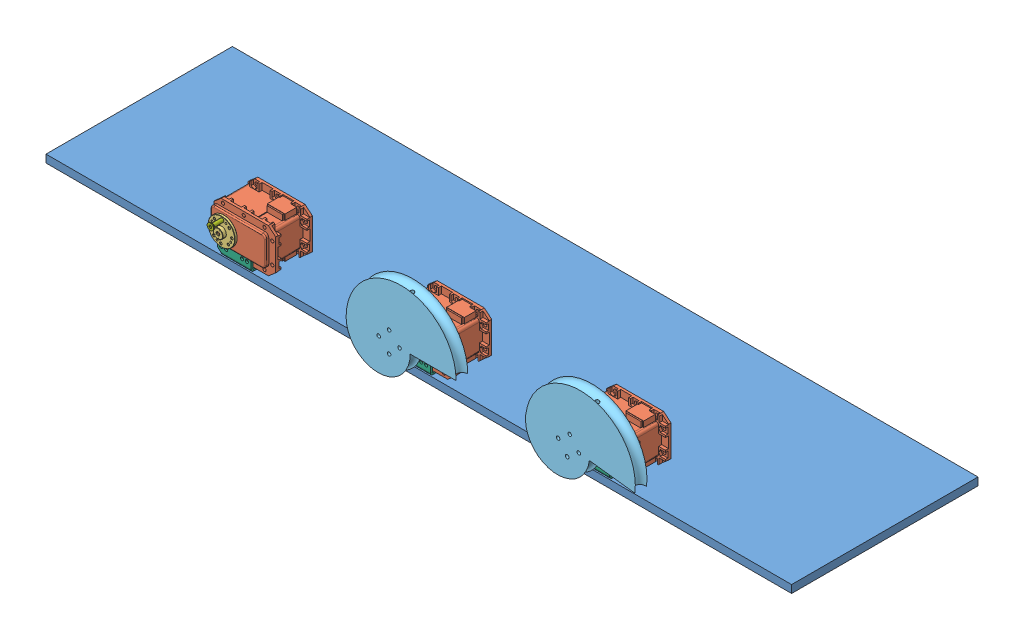
SolidWorks assembly Testing Rig, configuration Default. Lengths in mm.
Overall size (609.6 81.47 166.18).
21 component instances, 7 part files, 30 mates.
Components (placement in the parent):
- Servo Test Plate-1: Servo Test Plate [Default] at (-31.9678 4.9345 11.3595) size (609.6 6.35 152.4)
- MX-28T-1: MX-28T [Default] at (-172.2343 83.1368 48.302) x (0 1 0) z (0 0 1) size (35.6 53.27 43.4) (flexible)
  - MX-28T-1: MX-28T [Default] at (-50.8523 16.8335 22.7575) size (35.6 50.6 41.85)
  - HN07-N1-1: HN07-N1 [Default] at (-50.8523 16.8335 41.5075) x (-0.4309 -0.9024 0) z (-0.9024 0.4309 0) size (22 5.86 22)
  - HN07-i1-1: HN07-i1 [Default] at (-50.8523 16.8335 2.9575) x (0.322877 -0.946441 0) z (0.946441 0.322877 0) size (22 3.05 22)
- MX-28T-2: MX-28T [Default] at (-25.6343 83.1368 48.302) x (0 1 0) z (0 0 1) size (35.6 52.97 43.4) (flexible)
  - MX-28T-1: MX-28T [Default] at (-50.8523 16.8335 22.7575) size (35.6 50.6 41.85)
  - HN07-N1-1: HN07-N1 [Default] at (-50.8523 16.8335 41.5075) x (0.382157 0.924098 0) z (0.924098 -0.382157 0) size (22 5.86 22)
  - HN07-i1-1: HN07-i1 [Default] at (-50.8523 16.8335 2.9575) x (0.322877 -0.946441 0) z (0.946441 0.322877 0) size (22 3.05 22)
- MX-28T-3: MX-28T [Default] at (120.9657 83.1368 48.302) x (0 1 0) z (0 0 1) size (35.6 52.56 43.4) (flexible)
  - MX-28T-1: MX-28T [Default] at (-50.8523 16.8335 22.7575) size (35.6 50.6 41.85)
  - HN07-N1-1: HN07-N1 [Default] at (-50.8523 16.8335 41.5075) x (0.120217 0.992748 0) z (0.992748 -0.120217 0) size (22 5.86 22)
  - HN07-i1-1: HN07-i1 [Default] at (-50.8523 16.8335 2.9575) x (0.322877 -0.946441 0) z (0.946441 0.322877 0) size (22 3.05 22)
- Nautilus Horn-1: Nautilus Horn [Default] at (-189.0678 32.2846 96.572) x (-0.998607 0.052766 0) z (0 0 1) size (89.93 71.18 9.53) (hidden)
- Nautilus Horn-2: Nautilus Horn [Default] at (-42.4678 32.2844 96.572) x (1 0.00057 0) z (0 0 1) size (89.93 71.18 9.53)
- Nautilus Horn-3: Nautilus Horn [Default] at (104.1322 32.2844 96.572) x (0.992748 -0.120217 0) z (0 0 1) size (89.93 71.18 9.53)
- FR07-S101 Bracket-1: FR07-S101 Bracket [Default] at (-181.0678 11.2845 71.0595) size (27.5 8.6 33.01)
- FR07-S101 Bracket-2: FR07-S101 Bracket [Default] at (-34.4678 11.2845 71.0595) size (27.5 8.6 33.01)
- FR07-S101 Bracket-3: FR07-S101 Bracket [Default] at (112.1322 11.2845 71.0595) size (27.5 8.6 33.01)
- socket countersunk head screw_am-1: socket countersunk head screw_am [B18.3.5M - 3 x 0.5 x 12 Socket FCHS  -- 12N] at (-188.846 4.3245 63.2813) x (0 1 0) z (0 0 1) size (12 5.35 5.35)
- socket countersunk head screw_am-2: socket countersunk head screw_am [B18.3.5M - 3 x 0.5 x 12 Socket FCHS  -- 12N] at (-188.6193 40.7729 101.3345) x (0 0 -1) z (1 0 0) size (12 5.35 5.35)
Mates (geometry in assembly coordinates):
- Concentric2: concentric aligned: cylinder of MX-28T-1/HN07-N1-1 through (-189.0678 32.2845 94.952) axis (0 0 -1) radius 11; cylinder of Nautilus Horn-1 through (-189.0678 32.2846 101.3345) axis (0 0 -1) radius 4.0005
- Concentric3: concentric anti-aligned: cylinder of MX-28T-1/HN07-N1-1 through (-189.5163 23.7963 88.0452) axis (0 0 1) radius 0.8; cylinder of Nautilus Horn-1 through (-189.5163 23.7963 91.8095) axis (0 0 -1) radius 1.45
- Parallel1: parallel anti-aligned: plane of Servo Test Plate-1 through (-31.9678 11.2845 11.3595) normal (0 1 0); plane of MX-28T-1/MX-28T-1 through (-195.0678 14.4845 58.0595) normal (0 -1 0)
- Coincident2: coincident anti-aligned: plane of MX-28T-1/MX-28T-1 through (-189.0678 32.2845 56.0595) normal (0 0 -1); plane of FR07-S101 Bracket-1 through (-169.0678 13.2845 56.0595) normal (0 0 1)
- Concentric4: concentric aligned: cylinder of MX-28T-1/MX-28T-1 through (-176.5678 17.2845 71.0595) axis (0 0 -1) radius 1.35; cylinder of FR07-S101 Bracket-1 through (-176.5678 17.2845 87.5595) axis (0 0 -1) radius 1.3
- Coincident3: coincident anti-aligned: plane of Servo Test Plate-1 through (-31.9678 11.2845 11.3595) normal (0 1 0); plane of FR07-S101 Bracket-1 through (-169.0678 11.2845 85.5595) normal (0 -1 0)
- Coincident4: coincident aligned: plane of Servo Test Plate-1 through (-336.7678 11.2845 87.5595) normal (0 0 1); plane of FR07-S101 Bracket-1 through (-169.0678 19.8845 87.5595) normal (0 0 1)
- Coincident5: coincident anti-aligned: plane of MX-28T-1/HN07-N1-1 through (-189.0678 32.2845 91.8095) normal (0 0 1); plane of Nautilus Horn-1 through (-189.0678 32.2846 91.8095) normal (0 0 -1)
- Concentric5: concentric aligned: cylinder of MX-28T-2/HN07-N1-1 through (-42.4678 32.2845 94.952) axis (0 0 -1) radius 4; cylinder of Nautilus Horn-2 through (-42.4678 32.2844 101.3345) axis (0 0 -1) radius 4.0005
- Coincident7: coincident anti-aligned: plane of MX-28T-2/HN07-N1-1 through (-42.4678 32.2845 91.8095) normal (0 0 1); plane of Nautilus Horn-2 through (-42.4678 32.2844 91.8095) normal (0 0 -1)
- Concentric6: concentric anti-aligned: cylinder of MX-28T-2/HN07-N1-1 through (-42.4726 40.7845 88.0452) axis (0 0 1) radius 0.8; cylinder of Nautilus Horn-2 through (-42.4726 40.7845 91.8095) axis (0 0 -1) radius 1.45
- Coincident8: coincident anti-aligned: plane of MX-28T-2/MX-28T-1 through (-42.4678 32.2845 56.0595) normal (0 0 -1); plane of FR07-S101 Bracket-2 through (-22.4678 13.2845 56.0595) normal (0 0 1)
- Concentric7: concentric aligned: cylinder of MX-28T-2/MX-28T-1 through (-46.9678 17.2845 71.0595) axis (0 0 -1) radius 1.35; cylinder of FR07-S101 Bracket-2 through (-46.9678 17.2845 87.5595) axis (0 0 -1) radius 1.3
- Coincident9: coincident anti-aligned: plane of Servo Test Plate-1 through (-31.9678 11.2845 11.3595) normal (0 1 0); plane of FR07-S101 Bracket-2 through (-22.4678 11.2845 85.5595) normal (0 -1 0)
- Coincident10: coincident aligned: plane of Servo Test Plate-1 through (-336.7678 11.2845 87.5595) normal (0 0 1); plane of FR07-S101 Bracket-2 through (-22.4678 19.8845 87.5595) normal (0 0 1)
- Concentric8: concentric aligned: cylinder of MX-28T-2/MX-28T-1 through (-29.9678 17.2845 71.0595) axis (0 0 -1) radius 1.35; cylinder of FR07-S101 Bracket-2 through (-29.9678 17.2845 87.5595) axis (0 0 -1) radius 1.3
- Distance2: distance = 101.6 mm anti-aligned: plane of MX-28T-1/MX-28T-1 through (-156.0678 20.0845 53.3095) normal (1 0 0); plane of MX-28T-2/MX-28T-1 through (-54.4678 44.4845 53.3095) normal (-1 0 0)
- Coincident12: coincident anti-aligned: plane of MX-28T-3/MX-28T-1 through (104.1322 32.2845 56.0595) normal (0 0 -1); plane of FR07-S101 Bracket-3 through (124.1322 13.2845 56.0595) normal (0 0 1)
- Concentric11: concentric aligned: cylinder of MX-28T-3/MX-28T-1 through (99.6322 17.2845 71.0595) axis (0 0 -1) radius 1.35; cylinder of FR07-S101 Bracket-3 through (99.6322 17.2845 87.5595) axis (0 0 -1) radius 1.3
- Concentric12: concentric aligned: cylinder of MX-28T-3/MX-28T-1 through (116.6322 17.2845 71.0595) axis (0 0 -1) radius 1.35; cylinder of FR07-S101 Bracket-3 through (116.6322 17.2845 87.5595) axis (0 0 -1) radius 1.3
- Coincident13: coincident anti-aligned: plane of Servo Test Plate-1 through (-31.9678 11.2845 11.3595) normal (0 1 0); plane of FR07-S101 Bracket-3 through (124.1322 11.2845 85.5595) normal (0 -1 0)
- Coincident14: coincident aligned: plane of Servo Test Plate-1 through (-336.7678 11.2845 87.5595) normal (0 0 1); plane of FR07-S101 Bracket-3 through (124.1322 19.8845 87.5595) normal (0 0 1)
- Concentric13: concentric aligned: cylinder of MX-28T-3/HN07-N1-1 through (104.1322 32.2845 94.952) axis (0 0 -1) radius 4; cylinder of Nautilus Horn-3 through (104.1322 32.2844 101.3345) axis (0 0 -1) radius 4.0005
- Coincident15: coincident anti-aligned: circle of MX-28T-3/HN07-N1-1; plane of Nautilus Horn-3 through (104.1322 32.2844 91.8095) normal (0 0 -1)
- Concentric14: concentric aligned: cylinder of MX-28T-3/HN07-N1-1 through (105.1541 40.7228 91.8095) axis (0 0 -1) radius 0.75; cylinder of Nautilus Horn-3 through (105.1541 40.7228 91.8095) axis (0 0 -1) radius 1.45
- Distance3: distance = 101.6 mm anti-aligned: plane of MX-28T-2/MX-28T-1 through (-9.4678 20.0845 53.3095) normal (1 0 0); plane of MX-28T-3/MX-28T-1 through (92.1322 44.4845 53.3095) normal (-1 0 0)
- Coincident17: coincident anti-aligned: plane of Servo Test Plate-1 through (-31.9678 4.9345 11.3595) normal (1 0 0); plane of MX-28T-2/MX-28T-1 through (-31.9678 32.2845 71.0595) normal (-1 0 0)
- Coincident18: coincident aligned: cone of Servo Test Plate-1 through (-188.846 4.9345 63.2813) axis (0 1 0); cone of socket countersunk head screw_am-1 through (-188.846 5.0095 63.2813) axis (0 1 0)
- Concentric15: concentric aligned: cylinder of Nautilus Horn-1 through (-188.6193 40.7729 91.8095) axis (0 0 -1) radius 1.45; cone of socket countersunk head screw_am-2 through (-188.6193 40.7729 100.6495) axis (0 0 -1)
- Coincident20: coincident aligned: plane of Nautilus Horn-1 through (-189.0678 32.2846 101.3345) normal (0 0 1); plane of socket countersunk head screw_am-2 through (-188.6193 40.7729 101.3345) normal (0 0 1)
